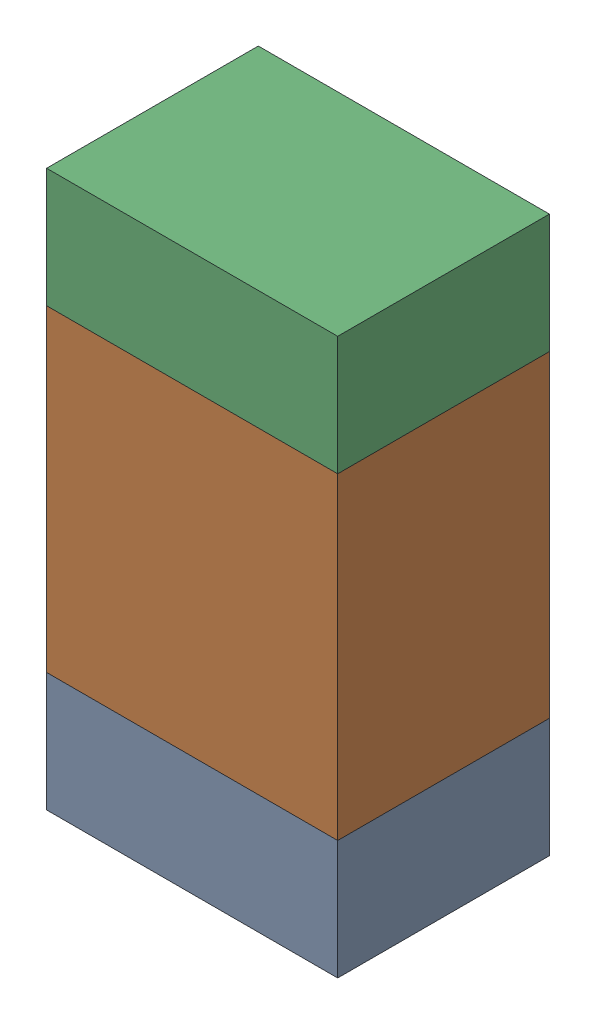
SolidWorks assembly R411PCB, configuration Default. Lengths in mm.
Overall size (0.55 1.05 0.4).
6 component instances, 2 part files, 0 mates.
Components (placement in the parent):
- 846483288-1: 846483288 [Default] at (124.2001 85.6876 -2.0638) size (0.55 0.22 0.4)
  - Extruded_12-1: Extruded_12 [Default] at origin size (0.55 0.22 0.4)
- 846483424-1: 846483424 [Default] at (124.2001 86.1001 -2.0638) size (0.55 0.6 0.4)
  - Extruded_13-1: Extruded_13 [Default] at origin size (0.55 0.6 0.4)
- 846483288-2: 846483288 [Default] at (124.2001 86.5126 -2.0638) size (0.55 0.22 0.4)
  - Extruded_12-1: Extruded_12 [Default] at origin size (0.55 0.22 0.4)
